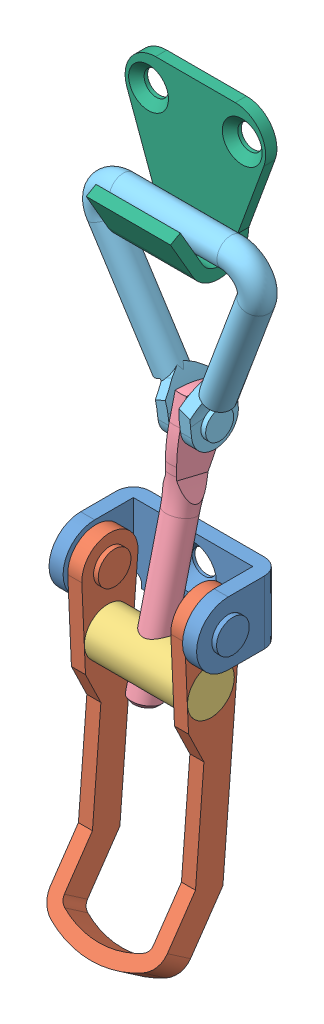
SolidWorks assembly ADJUSTABLE CLAMP, configuration LOCKED . Lengths in mm.
Overall size (39.54 155.02 32.17).
6 component instances, 6 part files, 15 mates.
Components (placement in the parent):
- CLAMP - BRACKET-1: CLAMP - BRACKET [Default] at origin
- CLAMP - HANDLE-1: CLAMP - HANDLE [Default] at origin
- SWIVEL PIN-1: SWIVEL PIN [Default] at (0 -3.0558 -3.8626) x (1 0 0) z (0 0.221472 0.975167)
- ADJUSTMENT SCREW-1: ADJUSTMENT SCREW [Default] at (0 6.7802 -6.2479) x (1 0 0) z (0 0.221472 0.975167)
- LATCH-1: LATCH [Default] at (0 12.0699 -12.0483) x (1 0 0) z (0 -0.243377 0.969932)
- CATCH-1: CATCH [Default] at (0 9 0)
Mates (geometry in assembly coordinates):
- Coincident2: coincident: plane of ? through (0 0 0) normal (1 0 0); plane of ADJUSTMENT SCREW-1 through (0 6.7802 -6.2479) normal (1 0 0)
- Coincident3: coincident: plane of assembly; plane of assembly; plane of CATCH-1 through (0 9 0) normal (1 0 0); plane of ADJUSTMENT SCREW-1 through (0 6.7802 -6.2479) normal (1 0 0)
- Coincident4: coincident: line of assembly; line of assembly; line of ADJUSTMENT SCREW-1 through (-3.7216 21.5604 1.9189) axis (1 0 0); line of LATCH-1 through (-5.6743 21.5604 1.9189) axis (1 0 0)
- Coincident5: coincident: plane of assembly; plane of assembly; plane of ADJUSTMENT SCREW-1 through (0 6.7802 -6.2479) normal (1 0 0); plane of LATCH-1 through (0 12.0699 -12.0483) normal (1 0 0)
- Concentric1: concentric: cylinder of assembly; cylinder of assembly; cylinder of CATCH-1 through (8.9001 59.2953 6.4) axis (-1 0 0) radius 4; cylinder of LATCH-1 through (-11.5 59.2953 6.4) axis (1 0 0) radius 3
- Concentric2: concentric: cylinder of assembly; cylinder of assembly; cylinder of SWIVEL PIN-1 through (0 -20.0896 12.0193) axis (0 0.971832 -0.235675) radius 3; cylinder of ADJUSTMENT SCREW-1 through (0 -10.2536 9.634) axis (0 0.971832 -0.235675) radius 3
- Coincident7: coincident: plane of ? through (0 0 0) normal (1 0 0); plane of SWIVEL PIN-1 through (0 -3.0558 -3.8626) normal (1 0 0)
- Distance3: distance = 10.12 mm: plane of assembly; plane of assembly; plane of ADJUSTMENT SCREW-1 through (0 6.7802 -6.2479) normal (0 0.975167 -0.221472); plane of SWIVEL PIN-1 through (0 -3.0558 -3.8626) normal (0 0.975167 -0.221472)
- Coincident8: coincident: line of ? through (-14.6065 -6.75 11.25) axis (1 0 0); line of ? through (-13.6578 -6.75 11.25) axis (1 0 0)
- Coincident9: coincident: plane of ? through (0 0 0) normal (1 0 0); plane of ? through (0 0 0) normal (1 0 0)
- Coincident10: coincident: line of SWIVEL PIN-1 through (-12.5 -18.7522 11.695) axis (1 0 0); line of ? through (-13.1132 -18.7522 11.695) axis (1 0 0)
- Parallel1: parallel: plane of ? through (0 0 0) normal (0 0 1); plane of ? through (0 0 0) normal (0 0 1)
- Distance4: distance = 20 mm: plane of CATCH-1 through (0 9 0) normal (0 0 1); plane of ? through (0 0 0) normal (0 0 1)
- Distance5: distance = 9 mm: plane of CATCH-1 through (0 9 0) normal (0 1 0); plane of ? through (0 0 0) normal (0 1 0)
- Coincident11: coincident: plane of ? through (0 -20.8683 0) normal (0 0 -1); plane of CATCH-1 through (-0.0999 62.3909 0) normal (0 0 -1)
